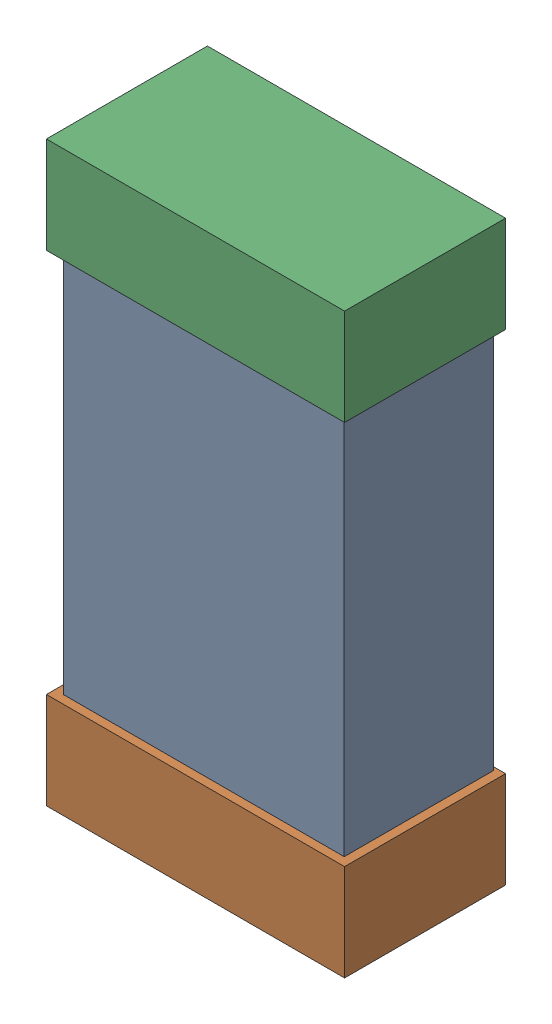
SolidWorks assembly C24, configuration Default. Lengths in mm.
Overall size (0.85 1.65 0.46).
6 component instances, 2 part files, 0 mates.
Components (placement in the parent):
- 432124816_34-1: 432124816_34 [Default] at (27.9501 60.7688 -0.8615) size (0.8 1.5 0.42)
  - Extruded (1)-1: Extruded (1) [Default] at origin size (0.8 1.5 0.42)
- 432138512_68-1: 432138512_68 [Default] at (27.9501 60.083 -0.8715) size (0.85 0.28 0.46)
  - Extruded-1: Extruded [Default] at origin size (0.85 0.28 0.46)
- 432138512_69-1: 432138512_69 [Default] at (27.9501 61.4545 -0.8715) size (0.85 0.28 0.46)
  - Extruded-1: Extruded [Default] at origin size (0.85 0.28 0.46)
